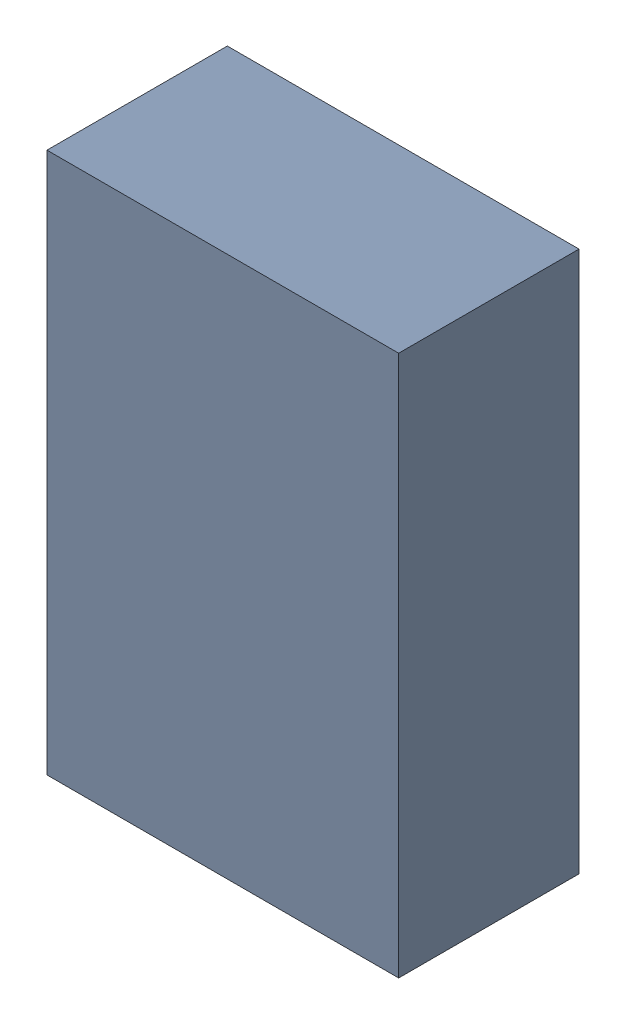
SolidWorks assembly D1, configuration ﾃﾞﾌｫﾙﾄ. Lengths in mm.
Overall size (1.95 3 1).
2 component instances, 1 part files, 0 mates.
Components (placement in the parent):
- 689264776-1: 689264776 [ﾃﾞﾌｫﾙﾄ] at (77.25 56.25 -2.2003) size (1.95 3 1)
  - Extruded_21-1: Extruded_21 [ﾃﾞﾌｫﾙﾄ] at origin size (1.95 3 1)
